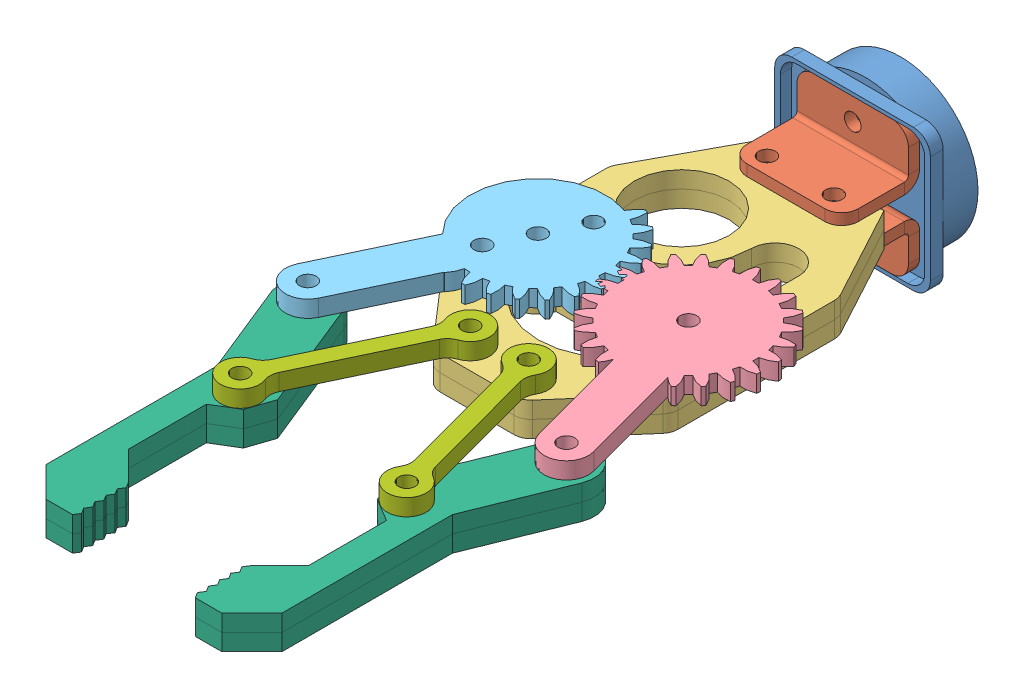
SolidWorks assembly Assem_01_robot_arm, configuration Default. Lengths in mm.
Overall size (82.65 27.75 138.32).
13 component instances, 7 part files, 31 mates.
Components (placement in the parent):
- part_05_base_of_extention-2: part_05_base_of_extention [Default] at (-1.2812 5.4684 30.0672) size (27.94 27.75 8.64)
- part_06_ext_base_arm-3: part_06_ext_base_arm [Default] at (-11.2812 9.5334 32.0672) x (0 0 -1) z (1 0 0) size (14 10 20)
- part_06_ext_base_arm-4: part_06_ext_base_arm [Default] at (8.7188 1.4034 32.0672) x (0 0 -1) z (-1 0 0) size (14 10 20)
- Arm 03-1: Arm 03 [Default] at (-1.6702 3.0334 74.6669) x (-1 0 0) z (0 0 -1) size (41 3 62)
- Arm 03-2: Arm 03 [Default] at (-1.6702 6.0334 74.6669) x (-1 0 0) z (0 0 -1) size (41 3 62)
- part_08_gear-1: part_08_gear [Default] at (11.899 9.0334 75.8081) x (0.259804 0 0.965661) z (-0.965661 0 0.259804) size (49.54 3 29.07)
- part_09_2nd_gear-1: part_09_2nd_gear [Default] at (-15.0948 9.0334 74.6183) x (0.049661 0 -0.998766) z (-0.998766 0 -0.049661) size (46.27 3 30.4)
- Arm 07-1: Arm 07 [Default] at (15.7587 6.0334 114.7997) x (0 1 0) z (0.375 0 -0.927025) size (3 21.49 60.01)
- Arm 07-2: Arm 07 [Default] at (15.7587 3.0334 114.7997) x (0 1 0) z (0.375 0 -0.927025) size (3 21.49 60.01)
- Arm 07-3: Arm 07 [Default] at (-24.3161 3.0334 112.88) x (0 -1 0) z (-0.375 0 -0.927025) size (3 21.49 60.01)
- Arm 07-4: Arm 07 [Default] at (-24.3161 6.0334 112.88) x (0 -1 0) z (-0.375 0 -0.927025) size (3 21.49 60.01)
- part_10_4x_bar-1: part_10_4x_bar [Default] at (-13.5557 9.0334 109.0694) x (0.428092 0 -0.903735) z (0 1 0) size (38 7 3)
- part_10_4x_bar-2: part_10_4x_bar [Default] at (7.6067 9.0334 110.0292) x (-0.259804 0 -0.965661) z (0 1 0) size (38 7 3)
Mates (geometry in assembly coordinates):
- Coincident7: coincident anti-aligned: plane of part_05_base_of_extention-2 through (9.6408 -4.1836 30.0672) normal (0 0 1); plane of part_06_ext_base_arm-3 through (8.7188 9.5334 30.0672) normal (0 0 -1)
- Symmetric3: symmetric anti-aligned: plane of part_05_base_of_extention-2 through (-11.1872 17.5334 32.0992) normal (0 -1 0); plane of part_05_base_of_extention-2 through (8.7188 17.5334 32.0672) normal (0 1 0); plane of part_06_ext_base_arm-3 through (-14.2352 -3.5486 32.0992) normal (1 0 0)
- Symmetric4: symmetric anti-aligned: plane of part_05_base_of_extention-2 through (-14.2352 -3.5486 32.0992) normal (1 0 0); plane of part_05_base_of_extention-2 through (11.6728 -3.5486 32.0992) normal (-1 0 0)
- Width1: width anti-aligned: plane of part_06_ext_base_arm-3 through (8.7188 7.5334 32.8038) normal (1 0 0); plane of part_06_ext_base_arm-3 through (-11.2812 10.27 32.8038) normal (-1 0 0); plane of part_05_base_of_extention-2 through (11.6728 -3.5486 32.0992) normal (-1 0 0); plane of part_05_base_of_extention-2 through (-14.2352 -3.5486 32.0992) normal (1 0 0)
- Coincident14: coincident anti-aligned: plane of part_05_base_of_extention-2 through (9.6408 -4.1836 30.0672) normal (0 0 1); plane of part_06_ext_base_arm-4 through (-11.2812 1.4034 30.0672) normal (0 0 -1)
- Coincident15: coincident anti-aligned: plane of part_05_base_of_extention-2 through (-11.1872 -6.5966 32.0992) normal (0 1 0); plane of part_06_ext_base_arm-4 through (-11.2812 -6.5966 32.0672) normal (0 -1 0)
- Width2: width aligned: plane of part_06_ext_base_arm-4 through (8.7188 0.6668 32.8038) normal (1 0 0); plane of part_06_ext_base_arm-4 through (-11.2812 3.4034 32.8038) normal (-1 0 0); plane of part_05_base_of_extention-2 through (-14.2352 -3.5486 32.0992) normal (1 0 0); plane of part_05_base_of_extention-2 through (11.6728 -3.5486 32.0992) normal (-1 0 0)
- Coincident16: coincident anti-aligned: plane of Arm 03-1 through (-1.6702 4.5334 74.6669) normal (0 1 0); plane of Arm 03-2 through (-1.6702 4.5334 74.6669) normal (0 -1 0)
- Coincident17: coincident aligned: line of Arm 03-1 through (-12.6702 4.5334 37.0672) axis (-0.475 0 0.879986); line of Arm 03-2 through (-12.6702 4.5334 37.0672) axis (-0.475 0 0.879986)
- Coincident18: coincident aligned: line of Arm 03-1 through (-21.4358 4.5334 85.5131) axis (0.655522 0 0.755176); line of Arm 03-2 through (-21.4358 4.5334 85.5131) axis (0.655522 0 0.755176)
- Coincident21: coincident aligned: circle of part_06_ext_base_arm-3; circle of Arm 03-2
- Coincident22: coincident aligned: circle of part_06_ext_base_arm-3; circle of Arm 03-2
- Coincident25: coincident anti-aligned: plane of Arm 03-2 through (-1.6702 7.5334 74.6669) normal (0 1 0); plane of part_08_gear-1 through (11.062 7.5334 87.3295) normal (0 -1 0)
- Coincident26: coincident aligned: circle of Arm 03-2; circle of part_08_gear-1
- Coincident27: coincident anti-aligned: plane of Arm 03-2 through (-1.6702 7.5334 74.6669) normal (0 1 0); plane of part_09_2nd_gear-1 through (-15.1702 7.5334 74.6669) normal (0 -1 0)
- Coincident28: coincident aligned: cylinder of Arm 03-1 through (-15.1702 4.5334 74.6669) axis (0 -1 0) radius 1.5; circle of part_09_2nd_gear-1
- Coincident37: coincident anti-aligned: plane of Arm 07-1 through (28.3053 4.5334 109.2717) normal (0 -1 0); plane of Arm 07-2 through (28.3053 4.5334 109.2717) normal (0 1 0)
- Coincident38: coincident aligned: line of Arm 07-1 through (31.1866 4.5334 117.2316) axis (0.100224 0 0.994965); line of Arm 07-2 through (31.1866 4.5334 117.2316) axis (0.100224 0 0.994965)
- Coincident39: coincident aligned: line of Arm 07-1 through (36.1923 4.5334 100.1178) axis (-0.280733 0 0.959786); line of Arm 07-2 through (36.1923 4.5334 100.1178) axis (-0.280733 0 0.959786)
- Coincident40: coincident anti-aligned: plane of part_08_gear-1 through (11.062 7.5334 87.3295) normal (0 -1 0); plane of Arm 07-1 through (28.3053 7.5334 109.2717) normal (0 1 0)
- Coincident41: coincident aligned: circle of part_08_gear-1; circle of Arm 07-1
- Coincident42: coincident anti-aligned: plane of Arm 07-3 through (-24.3161 4.5334 112.88) normal (0 1 0); plane of Arm 07-4 through (-24.3161 4.5334 112.88) normal (0 -1 0)
- Coincident43: coincident aligned: line of Arm 07-3 through (-26.3896 4.5334 121.0874) axis (-0.000553 0 1); line of Arm 07-4 through (-26.3896 4.5334 121.0874) axis (-0.000553 0 1)
- Parallel1: parallel aligned: line of Arm 07-4 through (-33.0762 4.5334 104.5577) axis (0.375 0 0.927025); line of Arm 07-3 through (-33.0762 4.5334 104.5577) axis (0.375 0 0.927025)
- Coincident45: coincident aligned: circle of Arm 07-3; circle of Arm 07-4
- Coincident47: coincident anti-aligned: plane of part_09_2nd_gear-1 through (-15.1702 7.5334 74.6669) normal (0 -1 0); plane of Arm 07-4 through (-24.3161 7.5334 112.88) normal (0 1 0)
- Coincident48: coincident aligned: circle of part_09_2nd_gear-1; circle of Arm 07-4
- Coincident49: coincident aligned: circle of Arm 03-2; circle of part_10_4x_bar-1
- Coincident51: coincident aligned: circle of Arm 07-4; cylinder of part_10_4x_bar-1 through (-20.1911 10.5334 123.0773) axis (0 -1 0) radius 1.5
- Coincident54: coincident aligned: circle of Arm 03-2; circle of part_10_4x_bar-2
- Coincident55: coincident aligned: circle of Arm 07-1; circle of part_10_4x_bar-2
